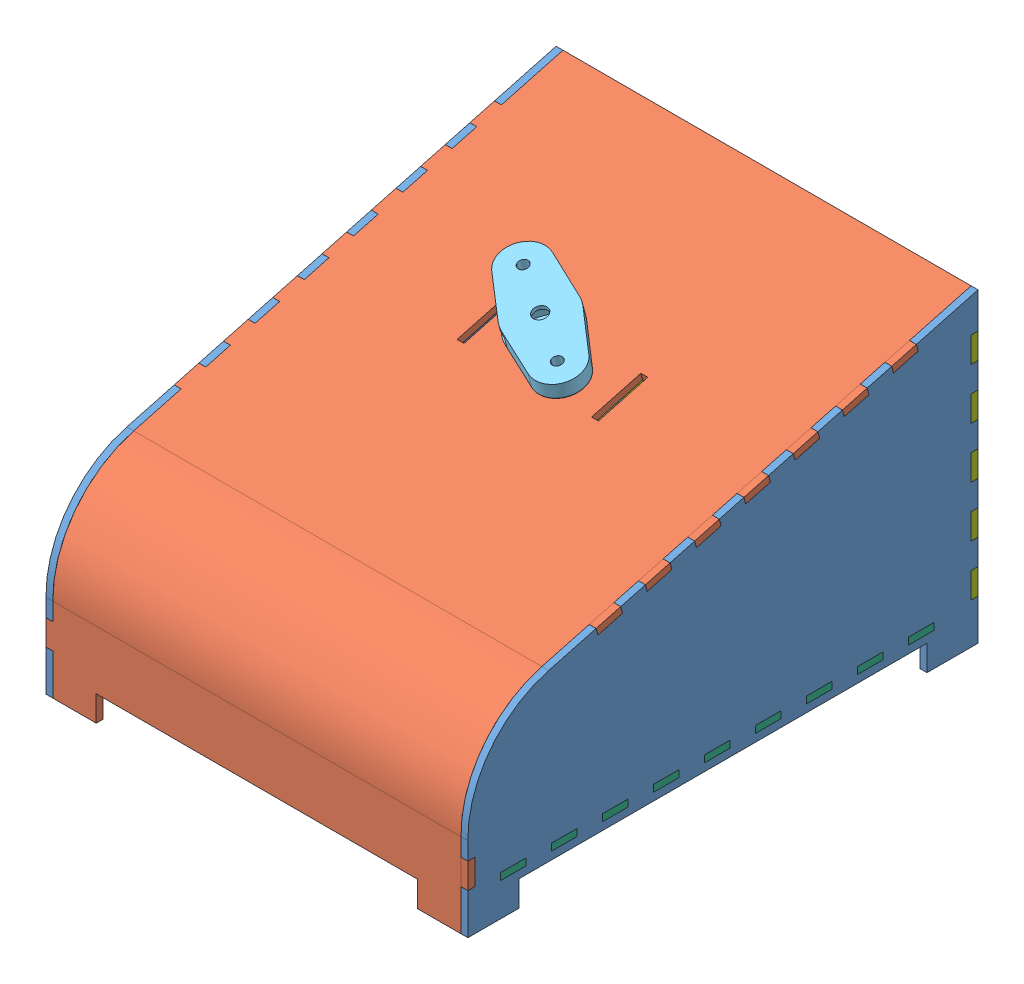
SolidWorks assembly pov display Assem 1.0, configuration Default. Lengths in mm.
Overall size (165.4 122.01 200.7).
9 component instances, 7 part files, 16 mates.
Components (placement in the parent):
- side panel life 2.0-2: side panel life 2.0 [Default] at origin size (2.7 120 200.01)
- pov top-1: pov top [Default] x (0 0 -1) z (1 0 0) size (200.7 120 165.4)
- side panel life 2.0-3: side panel life 2.0 [Default] at (-162.7 0 0) size (2.7 120 200.01)
- motor sub assembly-1: motor sub assembly [Default] at (-80 -12.4866 -29.2298) x (0 -0.258819 0.965926) z (-1 0 0) size (51.72 70.2 61.54)
  - pov display motor-1: pov display motor [Default] at origin size (32.51 63.2 29)
  - spur gear_din-4: spur gear_din [DIN - Spur gear 0.7M 12T 20PA 6FW ---S12B6H10L3N] at (0 57.2 0) x (0 1 0) z (-0.546944 0 0.837169) size (10 9.53 9.53)
  - motor cupling-1: motor cupling [Default] at (0 63.2 0) x (0.546944 0 -0.837169) z (0 1 0) size (57.83 24 17)
- base panel-1: base panel [Default] at (-80 -47 -1.2) size (165.4 2.7 197)
- pov back panel-1: pov back panel [Default] at (-80 3.5 -100) size (165.4 95 2.7)
Mates (geometry in assembly coordinates):
- InPlace2: in place: plane of pov top-1 through (0 0 0) normal (1 0 0); moOrthogonalPlaneRef_w of pov top-1 through (0 0 0) normal (0 1 0); plane of pov top-1 through (0 0 0) normal (0 0 -1); unknown of pov top-1
- Coincident4: coincident aligned: 
- Coincident5: coincident aligned: plane of pov top-1 through (0 0 0) normal (0 1 0)
- Coincident6: coincident anti-aligned: plane of pov top-1 through (0 0 0) normal (0 0 -1)
- Coincident7: coincident anti-aligned: plane of pov top-1 through (-160 -27.0742 97.3) normal (0 0 -1); plane of side panel life 2.0-3 through (-160 0 97.3) normal (0 0 1)
- Coincident8: coincident anti-aligned: plane of pov top-1 through (-162.7 -34 0) normal (0 1 0); plane of side panel life 2.0-3 through (-160 -34 0) normal (0 -1 0)
- Coincident9: coincident aligned: plane of pov top-1 through (-162.7 0 0) normal (-1 0 0); plane of side panel life 2.0-3 through (-162.7 0 0) normal (-1 0 0)
- Coincident10: coincident: point of pov top-1; point of motor sub assembly-1/pov display motor-1
- Coincident11: coincident anti-aligned: plane of pov top-1 through (-160 57.392 -100.6988) normal (0 -0.965926 -0.258819); plane of motor sub assembly-1/pov display motor-1 through (-80 34.8438 -16.5477) normal (0 0.965926 0.258819)
- Coincident12: coincident anti-aligned: line of pov top-1 through (2.7 34.8438 -16.5477) axis (-1 0 0); line of motor sub assembly-1/pov display motor-1 through (-92.4497 34.8438 -16.5477) axis (1 0 0)
- Coincident13: coincident anti-aligned: plane of side panel right 2.0-2 through (2.7 -44.3 0) normal (0 -1 0); plane of base panel-1 through (-80 -44.3 -1.2) normal (0 1 0)
- Coincident14: coincident anti-aligned: plane of side panel right 2.0-2 through (2.7 0 -82.7) normal (0 0 1); plane of base panel-1 through (0 -44.3 -82.7) normal (0 0 -1)
- Coincident15: coincident aligned: plane of side panel right 2.0-2 through (2.7 0 0) normal (1 0 0); plane of base panel-1 through (2.7 -44.3 67.3) normal (1 0 0)
- Coincident16: coincident aligned: plane of side panel life 2.0-2 through (2.7 0 0) normal (1 0 0); plane of pov back panel-1 through (2.7 3.5 -97.3) normal (1 0 0)
- Coincident17: coincident aligned: plane of side panel life 2.0-2 through (2.7 0 -100) normal (0 0 -1); plane of pov back panel-1 through (-80 3.5 -100) normal (0 0 -1)
- Coincident18: coincident anti-aligned: plane of side panel life 2.0-2 through (2.7 -34 0) normal (0 -1 0); plane of pov back panel-1 through (-80 -34 -97.3) normal (0 1 0)
